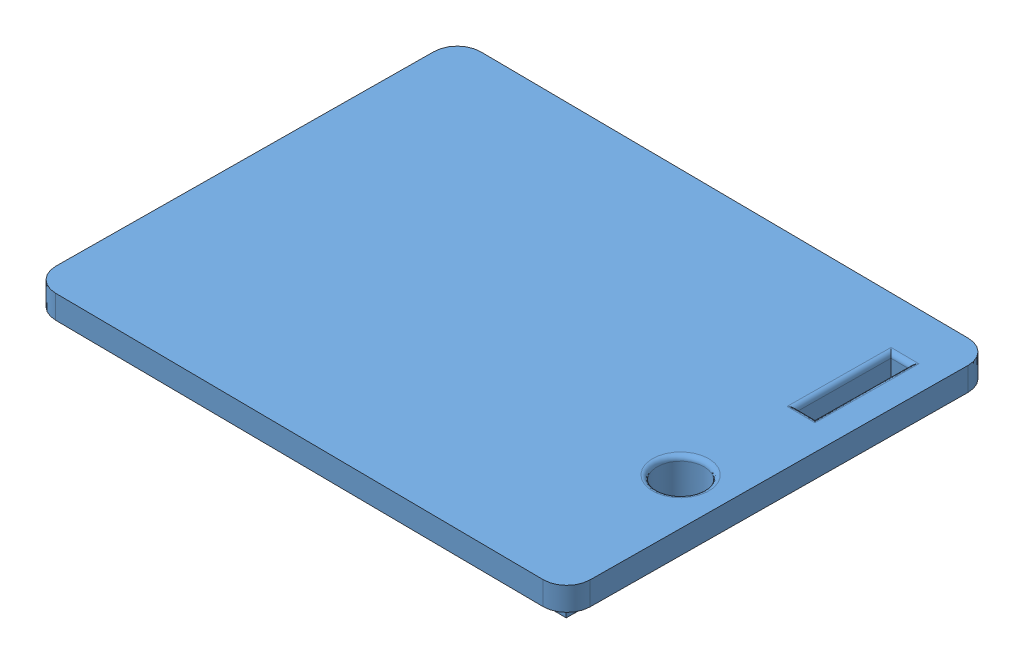
SolidWorks assembly AssemblySLDASM, configuration Default. Lengths in mm.
Overall size (115.78 8 91).
244 component instances, 43 part files, 6 mates.
Components (placement in the parent):
- Doos-1: Doos [Default] at (131.2672 32.8177 90.2383) x (0.999962 0 0.008727) z (-0.008727 0 0.999962) size (115 50 90) (hidden)
- IR_Communication.step-1: IR_Communication.step [Default] at (51.1638 53.2291 176.2275) x (0.999962 0 0.008727) z (0 1 0) size (107.95 83.18 36.35) (hidden)
  - Board.step-1: Board.step [Default] at origin size (107.95 83.18 0.41)
    - Open CASCADE STEP translator 7.5 1.1.1.step-1: Open CASCADE STEP translator 7.5 1.1.1.step [Default] at (0 0 -0.4115) size (107.95 83.18 0.41)
  - T2.step-1: T2.step [Default] at origin size (4.69 10.42 36.35)
    - 6118487888.step-1: 6118487888.step [Default] at (66.04 71.12 0) x (0 -1 0) z (0 0 1) size (10.42 4.69 36.35)
      - Tab.step-1: Tab.step [Default] at origin size (10.42 0.5 6.29)
      - Body.step-1: Body.step [Default] at (-2.6675 -1.495 3.805) size (10.42 4.69 8.76)
      - PinsArray.step-1: PinsArray.step [Default] at origin size (6.29 0.51 21.32)
  - T1.step-1: T1.step [Default] at origin size (4.69 10.42 36.35)
    - 6118487888.step-1: 6118487888.step [Default] at (66.04 85.09 0) x (0 -1 0) z (0 0 1) size (10.42 4.69 36.35)
      - Tab.step-1: Tab.step [Default] at origin size (10.42 0.5 6.29)
      - Body.step-1: Body.step [Default] at (-2.6675 -1.495 3.805) size (10.42 4.69 8.76)
      - PinsArray.step-1: PinsArray.step [Default] at origin size (6.29 0.51 21.32)
  - R27.step-1: R27.step [Default] at origin size (2 1.25 0.6)
    - 6118487168.step-1: 6118487168.step [Default] at (120.015 119.38 0) x (-1 0 0) z (0 0 1) size (2 1.25 0.6)
      - term1.step-1: term1.step [Default] at (-1 -0.625 0) size (0.35 1.25 0.6)
      - term2.step-1: term2.step [Default] at (0.65 -0.625 0) size (0.35 1.25 0.6)
      - Body.step-1: Body.step [Default] at (-0.65 -0.6125 0.006) size (10.42 4.69 8.76)
  - R26.step-1: R26.step [Default] at origin size (2 1.25 0.6)
    - 6118487168.step-1: 6118487168.step [Default] at (120.015 114.3 0) x (-1 0 0) z (0 0 1) size (2 1.25 0.6)
      - term1.step-1: term1.step [Default] at (-1 -0.625 0) size (0.35 1.25 0.6)
      - term2.step-1: term2.step [Default] at (0.65 -0.625 0) size (0.35 1.25 0.6)
      - Body.step-1: Body.step [Default] at (-0.65 -0.6125 0.006) size (10.42 4.69 8.76)
  - R25.step-1: R25.step [Default] at origin size (2 1.25 0.6)
    - 6118487168.step-1: 6118487168.step [Default] at (120.015 109.22 0) x (-1 0 0) z (0 0 1) size (2 1.25 0.6)
      - term1.step-1: term1.step [Default] at (-1 -0.625 0) size (0.35 1.25 0.6)
      - term2.step-1: term2.step [Default] at (0.65 -0.625 0) size (0.35 1.25 0.6)
      - Body.step-1: Body.step [Default] at (-0.65 -0.6125 0.006) size (10.42 4.69 8.76)
  - R24.step-1: R24.step [Default] at origin size (2 1.25 0.6)
    - 6118489168.step-1: 6118489168.step [Default] at (120.015 104.14 0) x (1 0 0) z (0 0 1) size (2 1.25 0.6)
      - term1-0.step-1: term1-0.step [Default] at (-1 -0.625 0) size (0.35 1.25 0.6)
      - term2-1.step-1: term2-1.step [Default] at (0.65 -0.625 0) size (0.35 1.25 0.6)
      - body-2.step-1: body-2.step [Default] at (-0.65 -0.6125 0.006) size (1.3 1.22 0.59)
  - R23.step-1: R23.step [Default] at origin size (1.25 2 0.6)
    - 6118488528.step-1: 6118488528.step [Default] at (54.61 111.76 0) x (0 1 0) z (0 0 1) size (2 1.25 0.6)
      - term1-3.step-1: term1-3.step [Default] at (-1 -0.625 0) size (0.35 1.25 0.6)
      - term2-4.step-1: term2-4.step [Default] at (0.65 -0.625 0) size (0.35 1.25 0.6)
      - body-5.step-1: body-5.step [Default] at (-0.65 -0.6125 0.006) size (1.3 1.22 0.59)
  - R22.step-1: R22.step [Default] at origin size (1.25 2 0.6)
    - 6118488528.step-1: 6118488528.step [Default] at (36.83 111.76 0) x (0 1 0) z (0 0 1) size (2 1.25 0.6)
      - term1-3.step-1: term1-3.step [Default] at (-1 -0.625 0) size (0.35 1.25 0.6)
      - term2-4.step-1: term2-4.step [Default] at (0.65 -0.625 0) size (0.35 1.25 0.6)
      - body-5.step-1: body-5.step [Default] at (-0.65 -0.6125 0.006) size (1.3 1.22 0.59)
  - R21.step-1: R21.step [Default] at origin size (1.25 2 0.6)
    - 6118488528.step-1: 6118488528.step [Default] at (111.76 111.76 0) x (0 1 0) z (0 0 1) size (2 1.25 0.6)
      - term1-3.step-1: term1-3.step [Default] at (-1 -0.625 0) size (0.35 1.25 0.6)
      - term2-4.step-1: term2-4.step [Default] at (0.65 -0.625 0) size (0.35 1.25 0.6)
      - body-5.step-1: body-5.step [Default] at (-0.65 -0.6125 0.006) size (1.3 1.22 0.59)
  - R20.step-1: R20.step [Default] at origin size (1.25 2 0.6)
    - 6118488528.step-1: 6118488528.step [Default] at (92.71 111.76 0) x (0 1 0) z (0 0 1) size (2 1.25 0.6)
      - term1-3.step-1: term1-3.step [Default] at (-1 -0.625 0) size (0.35 1.25 0.6)
      - term2-4.step-1: term2-4.step [Default] at (0.65 -0.625 0) size (0.35 1.25 0.6)
      - body-5.step-1: body-5.step [Default] at (-0.65 -0.6125 0.006) size (1.3 1.22 0.59)
  - R19.step-1: R19.step [Default] at origin size (1.25 2 0.6)
    - 6118488528.step-1: 6118488528.step [Default] at (82.55 111.44 0) x (0 1 0) z (0 0 1) size (2 1.25 0.6)
      - term1-3.step-1: term1-3.step [Default] at (-1 -0.625 0) size (0.35 1.25 0.6)
      - term2-4.step-1: term2-4.step [Default] at (0.65 -0.625 0) size (0.35 1.25 0.6)
      - body-5.step-1: body-5.step [Default] at (-0.65 -0.6125 0.006) size (1.3 1.22 0.59)
  - R18.step-1: R18.step [Default] at origin size (1.25 2 0.6)
    - 6118488528.step-1: 6118488528.step [Default] at (63.5 111.76 0) x (0 1 0) z (0 0 1) size (2 1.25 0.6)
      - term1-3.step-1: term1-3.step [Default] at (-1 -0.625 0) size (0.35 1.25 0.6)
      - term2-4.step-1: term2-4.step [Default] at (0.65 -0.625 0) size (0.35 1.25 0.6)
      - body-5.step-1: body-5.step [Default] at (-0.65 -0.6125 0.006) size (1.3 1.22 0.59)
  - R17.step-1: R17.step [Default] at origin size (10.3 11.1 11.3)
    - 6118489488.step-1: 6118489488.step [Default] at (55.84 104.06 0) x (-1 0 0) z (0 0 1) size (10.3 11.1 11.3)
      - Body-6.step-1: Body-6.step [Default] at (0 0 0.1) size (10.3 10 6.2)
      - Leads.step-1: Leads.step [Default] at origin size (6.1 11.1 5.1)
  - R16.step-1: R16.step [Default] at origin size (10.3 11.1 11.3)
    - 6118489488.step-1: 6118489488.step [Default] at (41.87 104.06 0) x (-1 0 0) z (0 0 1) size (10.3 11.1 11.3)
      - Body-6.step-1: Body-6.step [Default] at (0 0 0.1) size (10.3 10 6.2)
      - Leads.step-1: Leads.step [Default] at origin size (6.1 11.1 5.1)
  - R15.step-1: R15.step [Default] at origin size (10.3 11.1 11.3)
    - 6118489488.step-1: 6118489488.step [Default] at (111.72 104.06 0) x (-1 0 0) z (0 0 1) size (10.3 11.1 11.3)
      - Body-6.step-1: Body-6.step [Default] at (0 0 0.1) size (10.3 10 6.2)
      - Leads.step-1: Leads.step [Default] at origin size (6.1 11.1 5.1)
  - R14.step-1: R14.step [Default] at origin size (10.3 11.1 11.3)
    - 6118489488.step-1: 6118489488.step [Default] at (97.75 104.06 0) x (-1 0 0) z (0 0 1) size (10.3 11.1 11.3)
      - Body-6.step-1: Body-6.step [Default] at (0 0 0.1) size (10.3 10 6.2)
      - Leads.step-1: Leads.step [Default] at origin size (6.1 11.1 5.1)
  - R13.step-1: R13.step [Default] at origin size (10.3 11.1 11.3)
    - 6118489488.step-1: 6118489488.step [Default] at (83.78 103.98 0) x (-1 0 0) z (0 0 1) size (10.3 11.1 11.3)
      - Body-6.step-1: Body-6.step [Default] at (0 0 0.1) size (10.3 10 6.2)
      - Leads.step-1: Leads.step [Default] at origin size (6.1 11.1 5.1)
  - R12.step-1: R12.step [Default] at origin size (10.3 11.1 11.3)
    - 6118489488.step-1: 6118489488.step [Default] at (69.81 104.06 0) x (-1 0 0) z (0 0 1) size (10.3 11.1 11.3)
      - Body-6.step-1: Body-6.step [Default] at (0 0 0.1) size (10.3 10 6.2)
      - Leads.step-1: Leads.step [Default] at origin size (6.1 11.1 5.1)
  - R9.step-1: R9.step [Default] at origin size (1.25 2 0.6)
    - 6118488528.step-1: 6118488528.step [Default] at (46.99 73.66 0) x (0 1 0) z (0 0 1) size (2 1.25 0.6)
      - term1-3.step-1: term1-3.step [Default] at (-1 -0.625 0) size (0.35 1.25 0.6)
      - term2-4.step-1: term2-4.step [Default] at (0.65 -0.625 0) size (0.35 1.25 0.6)
      - body-5.step-1: body-5.step [Default] at (-0.65 -0.6125 0.006) size (1.3 1.22 0.59)
  - R8.step-1: R8.step [Default] at origin size (1.25 2 0.6)
    - 6118488528.step-1: 6118488528.step [Default] at (83.82 76.835 0) x (0 1 0) z (0 0 1) size (2 1.25 0.6)
      - term1-3.step-1: term1-3.step [Default] at (-1 -0.625 0) size (0.35 1.25 0.6)
      - term2-4.step-1: term2-4.step [Default] at (0.65 -0.625 0) size (0.35 1.25 0.6)
      - body-5.step-1: body-5.step [Default] at (-0.65 -0.6125 0.006) size (1.3 1.22 0.59)
  - R7.step-1: R7.step [Default] at origin size (1.25 2 0.6)
    - 6118489088.step-1: 6118489088.step [Default] at (96.52 76.835 0) x (0 -1 0) z (0 0 1) size (2 1.25 0.6)
      - term1-7.step-1: term1-7.step [Default] at (-1 -0.625 0) size (0.35 1.25 0.6)
      - term2-8.step-1: term2-8.step [Default] at (0.65 -0.625 0) size (0.35 1.25 0.6)
      - body-9.step-1: body-9.step [Default] at (-0.65 -0.6125 0.006) size (1.3 1.22 0.59)
  - R6.step-1: R6.step [Default] at origin size (1.25 2 0.6)
    - 6118488528.step-1: 6118488528.step [Default] at (90.17 76.835 0) x (0 1 0) z (0 0 1) size (2 1.25 0.6)
      - term1-3.step-1: term1-3.step [Default] at (-1 -0.625 0) size (0.35 1.25 0.6)
      - term2-4.step-1: term2-4.step [Default] at (0.65 -0.625 0) size (0.35 1.25 0.6)
      - body-5.step-1: body-5.step [Default] at (-0.65 -0.6125 0.006) size (1.3 1.22 0.59)
  - R5.step-1: R5.step [Default] at origin size (1.25 2 0.6)
    - 6118489088.step-1: 6118489088.step [Default] at (77.47 76.835 0) x (0 -1 0) z (0 0 1) size (2 1.25 0.6)
      - term1-7.step-1: term1-7.step [Default] at (-1 -0.625 0) size (0.35 1.25 0.6)
      - term2-8.step-1: term2-8.step [Default] at (0.65 -0.625 0) size (0.35 1.25 0.6)
      - body-9.step-1: body-9.step [Default] at (-0.65 -0.6125 0.006) size (1.3 1.22 0.59)
  - R4.step-1: R4.step [Default] at origin size (1.25 2 0.6)
    - 6118489088.step-1: 6118489088.step [Default] at (41.91 81.28 0) x (0 -1 0) z (0 0 1) size (2 1.25 0.6)
      - term1-7.step-1: term1-7.step [Default] at (-1 -0.625 0) size (0.35 1.25 0.6)
      - term2-8.step-1: term2-8.step [Default] at (0.65 -0.625 0) size (0.35 1.25 0.6)
      - body-9.step-1: body-9.step [Default] at (-0.65 -0.6125 0.006) size (1.3 1.22 0.59)
  - R3.step-1: R3.step [Default] at origin size (1.25 2 0.6)
    - 6118488528.step-1: 6118488528.step [Default] at (41.91 66.04 0) x (0 1 0) z (0 0 1) size (2 1.25 0.6)
      - term1-3.step-1: term1-3.step [Default] at (-1 -0.625 0) size (0.35 1.25 0.6)
      - term2-4.step-1: term2-4.step [Default] at (0.65 -0.625 0) size (0.35 1.25 0.6)
      - body-5.step-1: body-5.step [Default] at (-0.65 -0.6125 0.006) size (1.3 1.22 0.59)
  - R2.step-1: R2.step [Default] at origin size (1.25 2 0.6)
    - 6118488528.step-1: 6118488528.step [Default] at (46.99 81.28 0) x (0 1 0) z (0 0 1) size (2 1.25 0.6)
      - term1-3.step-1: term1-3.step [Default] at (-1 -0.625 0) size (0.35 1.25 0.6)
      - term2-4.step-1: term2-4.step [Default] at (0.65 -0.625 0) size (0.35 1.25 0.6)
      - body-5.step-1: body-5.step [Default] at (-0.65 -0.6125 0.006) size (1.3 1.22 0.59)
  - R1.step-1: R1.step [Default] at origin size (1.25 2 0.6)
    - 6118489088.step-1: 6118489088.step [Default] at (46.99 66.04 0) x (0 -1 0) z (0 0 1) size (2 1.25 0.6)
      - term1-7.step-1: term1-7.step [Default] at (-1 -0.625 0) size (0.35 1.25 0.6)
      - term2-8.step-1: term2-8.step [Default] at (0.65 -0.625 0) size (0.35 1.25 0.6)
      - body-9.step-1: body-9.step [Default] at (-0.65 -0.6125 0.006) size (1.3 1.22 0.59)
  - IC4.step-1: IC4.step [Default] at origin size (3.9 4.9 1.65)
    - 6222031760.step-1: 6222031760.step [Default] at (101.8 111.125 0.1) size (3.9 4.9 1.65)
      - Extruded.step-1: Extruded.step [Default] at origin size (3.9 4.9 1.65)
  - IC3.step-1: IC3.step [Default] at origin size (3.9 4.9 1.65)
    - 6222031760.step-1: 6222031760.step [Default] at (73.46 111.125 0.1) size (3.9 4.9 1.65)
      - Extruded.step-1: Extruded.step [Default] at origin size (3.9 4.9 1.65)
  - IC2.step-1: IC2.step [Default] at origin size (3.9 4.9 1.65)
    - 6222031760.step-1: 6222031760.step [Default] at (45.72 111.76 0.1) size (3.9 4.9 1.65)
      - Extruded.step-1: Extruded.step [Default] at origin size (3.9 4.9 1.65)
  - IC1.step-1: IC1.step [Default] at origin size (9.4 6.35 2.18)
    - 6118489728.step-1: 6118489728.step [Default] at (100.09 53.345 1.09) x (1 0 0) z (0 1 0) size (9.4 2.18 6.35)
  - D5.step-1: D5.step [Default] at origin size (4.86 20.04 12.47)
    - 6118486528.step-1: 6118486528.step [Default] at (128.27 101.6 0) x (0 1 0) z (0 0 1) size (20.04 4.86 12.47)
      - Body-10.step-1: Body-10.step [Default] at (0 0 0.1) size (20.04 4.86 7.37)
      - Leads-11.step-1: Leads-11.step [Default] at origin size (18.28 0.5 5.1)
  - D4.step-1: D4.step [Default] at origin size (0.71 3.25 5.1)
    - 6118489568.step-1: 6118489568.step [Default] at (29.21 107.95 0) x (0 1 0) z (0 0 1) size (3.25 0.71 5.1)
      - Body-12.step-1: Body-12.step [Default] at (0 0 0.1)
      - Leads-13.step-1: Leads-13.step [Default] at origin size (3.25 0.71 5.1)
  - D3.step-1: D3.step [Default] at origin size (0.71 3.25 5.1)
    - 6118489568.step-1: 6118489568.step [Default] at (29.21 83.82 0) x (0 1 0) z (0 0 1) size (3.25 0.71 5.1)
      - Body-12.step-1: Body-12.step [Default] at (0 0 0.1)
      - Leads-13.step-1: Leads-13.step [Default] at origin size (3.25 0.71 5.1)
  - D2.step-1: D2.step [Default] at origin size (3.62 5.4 2.44)
    - 6118488128.step-1: 6118488128.step [Default] at (55.88 67.31 0) x (0 -1 0) z (0 0 1) size (5.4 3.62 2.44)
      - Body-14.step-1: Body-14.step [Default] at origin size (5.2 3.62 2.34)
      - FilletPin1.step-1: FilletPin1.step [Default] at origin size (1.14 2.08 1.15)
      - FilletPin2.step-1: FilletPin2.step [Default] at origin size (1.24 2.08 1.15)
  - D1.step-1: D1.step [Default] at origin size (3.62 5.4 2.44)
    - 6118488208.step-1: 6118488208.step [Default] at (55.88 79.67 0) x (0 1 0) z (0 0 1) size (5.4 3.62 2.44)
      - Body-15.step-1: Body-15.step [Default] at origin size (5.2 3.62 2.34)
      - FilletPin1-16.step-1: FilletPin1-16.step [Default] at origin size (1.14 2.08 1.15)
      - FilletPin2-17.step-1: FilletPin2-17.step [Default] at origin size (1.24 2.08 1.15)
  - CN21.step-1: CN21.step [Default] at origin size (11.05 3.3 0.25)
    - 6198538976.step-1: 6198538976.step [Default] at (56.4515 54.61 0) size (11.05 3.3 0.25)
      - Extruded-18.step-1: Extruded-18.step [Default] at origin size (11.05 3.3 0.25)
  - CN20.step-1: CN20.step [Default] at origin size (4.67 2.34 10.88)
    - 6118488448.step-1: 6118488448.step [Default] at (113.03 119.38 0) x (-1 0 0) z (0 0 1) size (4.67 2.34 10.88)
      - Body-19.step-1: Body-19.step [Default] at origin size (4.67 2.34 2.37)
      - LeadsArray.step-1: LeadsArray.step [Default] at origin size (3.5 0.96 10.88)
  - CN19.step-1: CN19.step [Default] at origin size (4.67 2.34 10.88)
    - 6118488448.step-1: 6118488448.step [Default] at (105.41 119.38 0) x (-1 0 0) z (0 0 1) size (4.67 2.34 10.88)
      - Body-19.step-1: Body-19.step [Default] at origin size (4.67 2.34 2.37)
      - LeadsArray.step-1: LeadsArray.step [Default] at origin size (3.5 0.96 10.88)
  - CN18.step-1: CN18.step [Default] at origin size (4.67 2.34 10.88)
    - 6118488448.step-1: 6118488448.step [Default] at (97.79 119.38 0) x (-1 0 0) z (0 0 1) size (4.67 2.34 10.88)
      - Body-19.step-1: Body-19.step [Default] at origin size (4.67 2.34 2.37)
      - LeadsArray.step-1: LeadsArray.step [Default] at origin size (3.5 0.96 10.88)
  - CN17.step-1: CN17.step [Default] at origin size (4.67 2.34 10.88)
    - 6118488448.step-1: 6118488448.step [Default] at (90.17 119.38 0) x (-1 0 0) z (0 0 1) size (4.67 2.34 10.88)
      - Body-19.step-1: Body-19.step [Default] at origin size (4.67 2.34 2.37)
      - LeadsArray.step-1: LeadsArray.step [Default] at origin size (3.5 0.96 10.88)
  - CN16.step-1: CN16.step [Default] at origin size (4.67 2.34 10.88)
    - 6118488448.step-1: 6118488448.step [Default] at (82.55 119.38 0) x (-1 0 0) z (0 0 1) size (4.67 2.34 10.88)
      - Body-19.step-1: Body-19.step [Default] at origin size (4.67 2.34 2.37)
      - LeadsArray.step-1: LeadsArray.step [Default] at origin size (3.5 0.96 10.88)
  - CN15.step-1: CN15.step [Default] at origin size (4.67 2.34 10.88)
    - 6118488448.step-1: 6118488448.step [Default] at (74.93 119.38 0) x (-1 0 0) z (0 0 1) size (4.67 2.34 10.88)
      - Body-19.step-1: Body-19.step [Default] at origin size (4.67 2.34 2.37)
      - LeadsArray.step-1: LeadsArray.step [Default] at origin size (3.5 0.96 10.88)
  - CN14.step-1: CN14.step [Default] at origin size (4.67 2.34 10.88)
    - 6118488448.step-1: 6118488448.step [Default] at (67.31 119.38 0) x (-1 0 0) z (0 0 1) size (4.67 2.34 10.88)
      - Body-19.step-1: Body-19.step [Default] at origin size (4.67 2.34 2.37)
      - LeadsArray.step-1: LeadsArray.step [Default] at origin size (3.5 0.96 10.88)
  - CN13.step-1: CN13.step [Default] at origin size (4.67 2.34 10.88)
    - 6118488448.step-1: 6118488448.step [Default] at (59.69 119.38 0) x (-1 0 0) z (0 0 1) size (4.67 2.34 10.88)
      - Body-19.step-1: Body-19.step [Default] at origin size (4.67 2.34 2.37)
      - LeadsArray.step-1: LeadsArray.step [Default] at origin size (3.5 0.96 10.88)
  - CN12.step-1: CN12.step [Default] at origin size (4.67 2.34 10.88)
    - 6118488448.step-1: 6118488448.step [Default] at (52.07 119.38 0) x (-1 0 0) z (0 0 1) size (4.67 2.34 10.88)
      - Body-19.step-1: Body-19.step [Default] at origin size (4.67 2.34 2.37)
      - LeadsArray.step-1: LeadsArray.step [Default] at origin size (3.5 0.96 10.88)
  - CN11.step-1: CN11.step [Default] at origin size (4.67 2.34 10.88)
    - 6118488448.step-1: 6118488448.step [Default] at (44.45 119.38 0) x (-1 0 0) z (0 0 1) size (4.67 2.34 10.88)
      - Body-19.step-1: Body-19.step [Default] at origin size (4.67 2.34 2.37)
      - LeadsArray.step-1: LeadsArray.step [Default] at origin size (3.5 0.96 10.88)
  - CN10.step-1: CN10.step [Default] at origin size (2.13 2.34 11.18)
    - 6118488368.step-1: 6118488368.step [Default] at (35.56 119.38 2.36) size (2.13 2.34 11.18)
  - CN9.step-1: CN9.step [Default] at origin size (2.13 2.34 11.18)
    - 6118488368.step-1: 6118488368.step [Default] at (86.995 54.61 2.36) size (2.13 2.34 11.18)
  - CN8.step-1: CN8.step [Default] at origin size (4.67 2.34 10.88)
    - 6118488448.step-1: 6118488448.step [Default] at (34.925 54.61 0) x (-1 0 0) z (0 0 1) size (4.67 2.34 10.88)
      - Body-19.step-1: Body-19.step [Default] at origin size (4.67 2.34 2.37)
      - LeadsArray.step-1: LeadsArray.step [Default] at origin size (3.5 0.96 10.88)
  - CN7.step-1: CN7.step [Default] at origin size (4.67 2.34 10.88)
    - 6118488448.step-1: 6118488448.step [Default] at (80.645 54.61 0) x (-1 0 0) z (0 0 1) size (4.67 2.34 10.88)
      - Body-19.step-1: Body-19.step [Default] at origin size (4.67 2.34 2.37)
      - LeadsArray.step-1: LeadsArray.step [Default] at origin size (3.5 0.96 10.88)
  - CN6.step-1: CN6.step [Default] at origin size (10.16 5.46 0.25)
    - 6198539856.step-1: 6198539856.step [Default] at (69.215 54.8005 0) size (10.16 5.46 0.25)
      - Extruded-20.step-1: Extruded-20.step [Default] at origin size (10.16 5.46 0.25)
  - CN5.step-1: CN5.step [Default] at origin size (10.16 5.46 0.25)
    - 6198540016.step-1: 6198540016.step [Default] at (43.815 54.4195 0) size (10.16 5.46 0.25)
      - Extruded-21.step-1: Extruded-21.step [Default] at origin size (10.16 5.46 0.25)
  - CN4.step-1: CN4.step [Default] at origin size (23.36 2.5 19)
    - 6118488608.step-1: 6118488608.step [Default] at (96.52 83.185 1.11) x (-1 0 0) z (0 1 0) size (23.36 19 2.5)
  - CN3.step-1: CN3.step [Default] at origin size (23.36 2.5 19)
    - 6118488608.step-1: 6118488608.step [Default] at (96.52 67.945 1.11) x (-1 0 0) z (0 1 0) size (23.36 19 2.5)
  - CN2.step-1: CN2.step [Default] at origin size (8.2 10.16 15.5)
    - 6118487008.step-1: 6118487008.step [Default] at (125.73 55.245 0) x (0 1 0) z (0 0 1) size (10.16 8.2 15.5)
      - Body-22.step-1: Body-22.step [Default] at (0 0 0.1) size (10.16 8.2 10.4)
      - Leads-23.step-1: Leads-23.step [Default] at origin size (6.18 1.1 5.1)
      - Leads-23.step-2: Leads-23.step [Default] at origin size (6.18 1.1 5.1)
  - CN1.step-1: CN1.step [Default] at origin size (3.3 11.05 0.25)
    - 6222032800.step-1: 6222032800.step [Default] at (35.56 69.7865 0) size (3.3 11.05 0.25)
      - Extruded-24.step-1: Extruded-24.step [Default] at origin size (3.3 11.05 0.25)
  - BTN1.step-1: BTN1.step [Default] at origin size (7.3 6 10.3)
    - 6118488288.step-1: 6118488288.step [Default] at (123.825 78.105 0) x (1 0 0) z (0 0 1) size (7.3 6 10.3)
      - Body-25.step-1: Body-25.step [Default] at (0 0 0.1) size (6 6 5.2)
      - Leads-26.step-1: Leads-26.step [Default] at origin size (7.3 5.3 5.1)
- Deksel-2: Deksel [Default] at (131.2672 87.8177 90.2383) x (0.999962 0 0.008727) z (0.008727 0 -0.999962) size (115 8 90)
Mates (geometry in assembly coordinates):
- Coincident1: coincident anti-aligned: plane of Doos-1 through (131.2672 52.8177 90.2383) normal (0 1 0); plane of IR_Communication.step-1/Board.step-1/Open CASCADE STEP translator 7.5 1.1.1.step-1 through (131.2921 52.8177 90.246) normal (0 -1 0)
- Coincident2: coincident anti-aligned: plane of Doos-1 through (185.6282 52.8177 49.1111) normal (-0.999962 0 -0.008727); plane of IR_Communication.step-1/Board.step-1/Open CASCADE STEP translator 7.5 1.1.1.step-1 through (184.9021 52.8177 132.3079) normal (0.999962 0 0.008727)
- Coincident3: coincident anti-aligned: plane of Doos-1 through (76.9062 52.8177 131.3654) normal (0.008727 0 -0.999962); plane of IR_Communication.step-1/Board.step-1/Open CASCADE STEP translator 7.5 1.1.1.step-1 through (76.9562 52.8177 131.3659) normal (-0.008727 0 0.999962)
- Coincident6: coincident anti-aligned: plane of Doos-1 through (131.2672 82.8177 90.2383) normal (0 1 0); plane of Deksel-2 through (131.2672 82.8177 90.2383) normal (0 -1 0)
- Coincident7: coincident anti-aligned: plane of Doos-1 through (77.6323 52.8177 48.1686) normal (0.999962 0 0.008727); plane of Deksel-2 through (76.9062 79.8177 131.3654) normal (-0.999962 0 -0.008727)
- Coincident8: coincident anti-aligned: plane of Doos-1 through (77.6323 52.8177 48.1686) normal (-0.008727 0 0.999962); plane of Deksel-2 through (77.6323 79.8177 48.1686) normal (0.008727 0 -0.999962)
